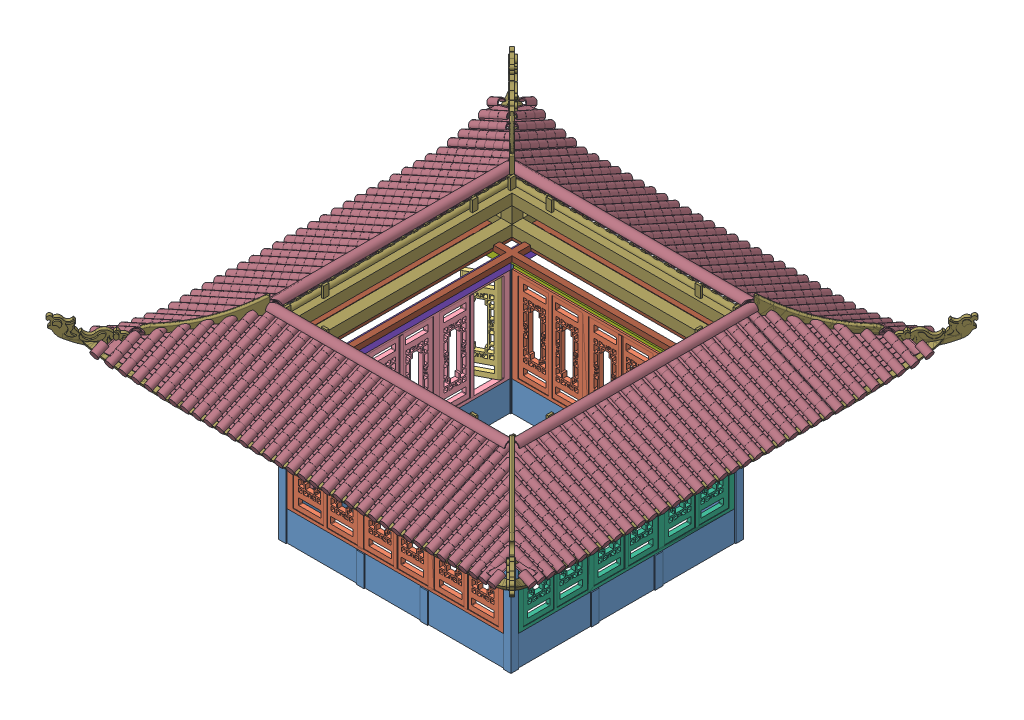
SolidWorks assembly 二层榫卯装配体, configuration 默认. Lengths in mm.
Overall size (9970.43 9546.15 11543.88).
17 component instances, 13 part files, 39 mates.
Components (placement in the parent):
- 二层梁柱-1: 二层梁柱 [默认] at (-2312.1162 -1286.0581 6420) size (4280 2400 4280)
- 二楼窗户合-1: 二楼窗户合 [默认] at (-2064.6162 -678.5581 2170) size (4160 1750 110)
- 窗户装配-1: 窗户装配 [默认] at (-3927.1162 42.9958 2157.9933) x (0 0 -1) z (1 0 0) size (4160 1750 543.88)
  - 二楼窗户单个-1: 二楼窗户单个 [默认] at (-286.4472 -721.554 1738.9724) x (-0.462898 0 -0.886412) z (0.886412 0 -0.462898) size (565 1690 80)
  - 二楼窗户合3-1: 二楼窗户合3 [默认] at (-4014.5067 -721.554 1645) size (4160 1750 110)
  - 窗户销-1: 窗户销 [默认] at (-269.5067 -779.054 1685) size (25 1750 25)
- 二楼窗户合-2: 二楼窗户合 [默认] at (-2064.6162 -678.5581 6310) size (4160 1750 110)
- 二楼窗户合2-1: 二楼窗户合2 [默认] at (1857.8838 -678.5581 6172.5) x (0 0 -1) z (1 0 0) size (4160 1750 110)
- 二层横杆-1: 二层横杆 [默认] at (-2872.1162 1013.9419 2230) size (5400 150 140)
- 二层横梁2-1: 二层横梁2 [默认] at (-2172.1162 1013.9419 6980) x (0 0 -1) z (1 0 0) size (5400 200 140)
- 二层横杆-2: 二层横杆 [默认] at (-2872.1162 1013.9419 6370) size (5400 150 140)
- 二层横梁2-2: 二层横梁2 [默认] at (1967.8838 1013.9419 6980) x (0 0 -1) z (1 0 0) size (5400 200 140)
- 斗拱整体-1: 斗拱整体 [默认] at (-2292.1162 1073.9419 6920) size (4980 380 6020)
- 斗拱整体2-1: 斗拱整体2 [默认] at (2467.8838 1073.9419 6400) x (0 0 -1) z (1 0 0) size (4980 430 6020)
- 二层三层交界-1: 二层三层交界 [默认] at (-2292.1162 1473.9419 7520) size (6500 100 6500)
- 二层屋顶木架-1: 二层屋顶木架 [默认] at (-2362.1162 2033.9419 6470) size (8627.15 1155.84 8627.15)
- 一面二层瓦-1: 一面二层瓦 [默认] at (-2052.1162 1719.201 7778.4212) x (1 0 0) z (0 -0.253518 0.967331) size (9788.95 7238.1 10036.79)
Mates (geometry in assembly coordinates):
- 重合1: coincident: plane of 二层梁柱-1 through (1857.8838 823.9419 2185) normal (0 0 1); plane of 二楼窗户合-1 through (1907.8838 821.4419 2185) normal (0 0 -1)
- 重合2: coincident: plane of 二层梁柱-1 through (1857.8838 923.9419 2185) normal (0 -1 0); plane of 二楼窗户合-1 through (1907.8838 923.9419 2185) normal (0 1 0)
- 重合3: coincident: plane of 二层梁柱-1 through (1907.8838 213.9419 2140) normal (-1 0 0); plane of 二楼窗户合-1 through (1907.8838 821.4419 2170) normal (1 0 0)
- 重合4: coincident: plane of 二层梁柱-1 through (-2217.1162 823.9419 2250) normal (-1 0 0); plane of 窗户装配-1/二楼窗户合3-1 through (-2217.1162 821.4419 2200) normal (1 0 0)
- 重合5: coincident: plane of 二层梁柱-1 through (-2217.1162 823.9419 2250) normal (0 1 0); plane of 窗户装配-1/二楼窗户合3-1 through (-2282.1162 823.9419 2200) normal (0 -1 0)
- 重合6: coincident: plane of 二层梁柱-1 through (-2312.1162 213.9419 2250) normal (0 0 1); plane of 窗户装配-1/二楼窗户合3-1 through (-2282.1162 821.4419 2250) normal (0 0 -1)
- 重合7: coincident: plane of 二层梁柱-1 through (-2202.1162 923.9419 6375) normal (0 -1 0); plane of 二楼窗户合-2 through (-2252.1162 923.9419 6325) normal (0 1 0)
- 重合8: coincident: plane of 二层梁柱-1 through (-2202.1162 823.9419 6375) normal (0 0 -1); plane of 二楼窗户合-2 through (-2252.1162 821.4419 6375) normal (0 0 1)
- 重合9: coincident: plane of 二层梁柱-1 through (-2172.1162 1113.9419 6420) normal (1 0 0); plane of 二楼窗户合-2 through (-2172.1162 -736.0581 6300) normal (-1 0 0)
- 重合10: coincident: plane of 二层梁柱-1 through (1872.8838 823.9419 6310) normal (1 0 0); plane of 二楼窗户合2-1 through (1872.8838 821.4419 6360) normal (-1 0 0)
- 重合11: coincident: plane of 二层梁柱-1 through (1872.8838 873.9419 2200) normal (0 -1 0); plane of 二楼窗户合2-1 through (1857.8838 873.9419 2250) normal (0 1 0)
- 重合12: coincident: plane of 二层梁柱-1 through (1967.8838 213.9419 2250) normal (0 0 1); plane of 二楼窗户合2-1 through (1857.8838 821.4419 2250) normal (0 0 -1)
- 重合13: coincident: plane of 二楼窗户合-1 through (422.8838 1013.9419 2160) normal (0 1 0); plane of 二层横杆-1 through (-2872.1162 1013.9419 2230) normal (0 -1 0)
- 重合14: coincident: plane of 二层梁柱-1 through (1967.8838 1113.9419 6420) normal (1 0 0); plane of 二层横杆-1 through (1967.8838 1113.9419 2140) normal (-1 0 0)
- 重合15: coincident: plane of 二层梁柱-1 through (1827.8838 1013.9419 2230) normal (0 0 -1); plane of 二层横杆-1 through (-2872.1162 1113.9419 2230) normal (0 0 1)
- 重合16: coincident: plane of 二层梁柱-1 through (-2312.1162 1113.9419 6420) normal (-1 0 0); plane of 二层横杆-2 through (-2312.1162 1113.9419 6280) normal (1 0 0)
- 重合17: coincident: plane of 二层梁柱-1 through (-2312.1162 1013.9419 6370) normal (0 0 -1); plane of 二层横杆-2 through (-2872.1162 1113.9419 6370) normal (0 0 1)
- 重合18: coincident: plane of 二楼窗户合-2 through (-2172.1162 1013.9419 6300) normal (0 1 0); plane of 二层横杆-2 through (-2872.1162 1013.9419 6370) normal (0 -1 0)
- 重合19: coincident: plane of 二层横杆-1 through (-2227.1162 1163.9419 2230) normal (-1 0 0); plane of 二层横梁2-1 through (-2227.1162 1163.9419 2160) normal (1 0 0)
- 重合20: coincident: plane of 二层横杆-1 through (-2872.1162 1163.9419 2160) normal (0 0 1); plane of 二层横梁2-1 through (-2257.1162 1163.9419 2160) normal (0 0 -1)
- 重合21: coincident: plane of 窗户装配-1/二楼窗户合3-1 through (-2292.1162 1013.9419 4982.5) normal (0 1 0); plane of 二层横梁2-1 through (-2172.1162 1013.9419 6980) normal (0 -1 0)
- 重合22: coincident: plane of 二层横杆-2 through (1882.8838 1163.9419 6370) normal (1 0 0); plane of 二层横梁2-2 through (1882.8838 863.9419 6400) normal (-1 0 0)
- 重合23: coincident: plane of 二层横杆-2 through (1267.8838 1163.9419 6380) normal (0 0 1); plane of 二层横梁2-2 through (1912.8838 863.9419 6380) normal (0 0 -1)
- 重合24: coincident: plane of 二楼窗户合2-1 through (1847.8838 1013.9419 6280) normal (0 1 0); plane of 二层横梁2-2 through (1967.8838 1013.9419 6980) normal (0 -1 0)
- 重合25: coincident: plane of 二层横梁2-2 through (1937.8838 1113.9419 1650) normal (-1 0 0); plane of 斗拱整体-1 through (1937.8838 1213.9419 1730) normal (1 0 0)
- 重合27: coincident: plane of 二层横梁2-2 through (1857.8838 1113.9419 1650) normal (0 0 1); plane of 斗拱整体-1 through (1937.8838 1213.9419 1650) normal (0 0 -1)
- 重合28: coincident: plane of 二层横梁2-2 through (1967.8838 1213.9419 6980) normal (0 1 0); plane of 斗拱整体-1 through (1847.8838 1213.9419 1740) normal (0 -1 0)
- 重合29: coincident: plane of 二层横杆-1 through (2377.8838 1063.9419 2170) normal (1 0 0); plane of 斗拱整体2-1 through (2377.8838 1213.9419 2170) normal (-1 0 0)
- 重合30: coincident: plane of 二层横杆-1 through (2457.8838 1063.9419 2170) normal (0 0 1); plane of 斗拱整体2-1 through (2457.8838 1213.9419 2170) normal (0 0 -1)
- 重合31: coincident: plane of 二层横杆-1 through (-2872.1162 1163.9419 2230) normal (0 1 0); plane of 斗拱整体2-1 through (2467.8838 1163.9419 2260) normal (0 -1 0)
- 重合32: coincident: plane of 斗拱整体-1 through (1967.8838 1493.9419 1610) normal (-1 0 0); plane of 二层三层交界-1 through (1967.8838 1573.9419 7520) normal (1 0 0)
- 重合33: coincident: plane of 斗拱整体2-1 through (2337.8838 1493.9419 2140) normal (0 0 1); plane of 二层三层交界-1 through (3087.8838 1573.9419 2140) normal (0 0 -1)
- 重合34: coincident: plane of 斗拱整体2-1 through (2467.8838 1473.9419 2260) normal (0 1 0); plane of 二层三层交界-1 through (3087.8838 1473.9419 6400) normal (0 -1 0)
- 重合35: coincident: plane of 二层三层交界-1 through (2207.8838 1473.9419 1020) normal (-1 0 0); plane of 二层屋顶木架-1 through (2207.8838 1573.9419 6470) normal (1 0 0)
- 重合36: coincident: plane of 二层三层交界-1 through (3087.8838 1473.9419 6640) normal (0 0 -1); plane of 二层屋顶木架-1 through (2037.8838 1573.9419 6640) normal (0 0 1)
- 重合37: coincident: plane of 二层三层交界-1 through (3087.8838 1573.9419 6400) normal (0 1 0); plane of 二层屋顶木架-1 through (-2362.1162 1573.9419 6470) normal (0 -1 0)
- 重合38: coincident: line of 二层屋顶木架-1 through (-162.1162 2233.9419 4270) axis (0 -1 0); line of 一面二层瓦-1 through (-162.1162 -582.6888 4270) axis (0 1 0)
- 相切1: tangent: plane of 二层屋顶木架-1 through (2148.0826 2277.3577 4732) normal (0.412423 0.910992 0); circle of 一面二层瓦-1
- 重合40: coincident: plane of 二层屋顶木架-1 through (3999.2072 2019.5084 8381.8259) normal (0.707107 0 -0.707107); plane of 一面二层瓦-1 through (2561.8431 1719.201 6944.4619) normal (-0.707107 0 0.707107)
